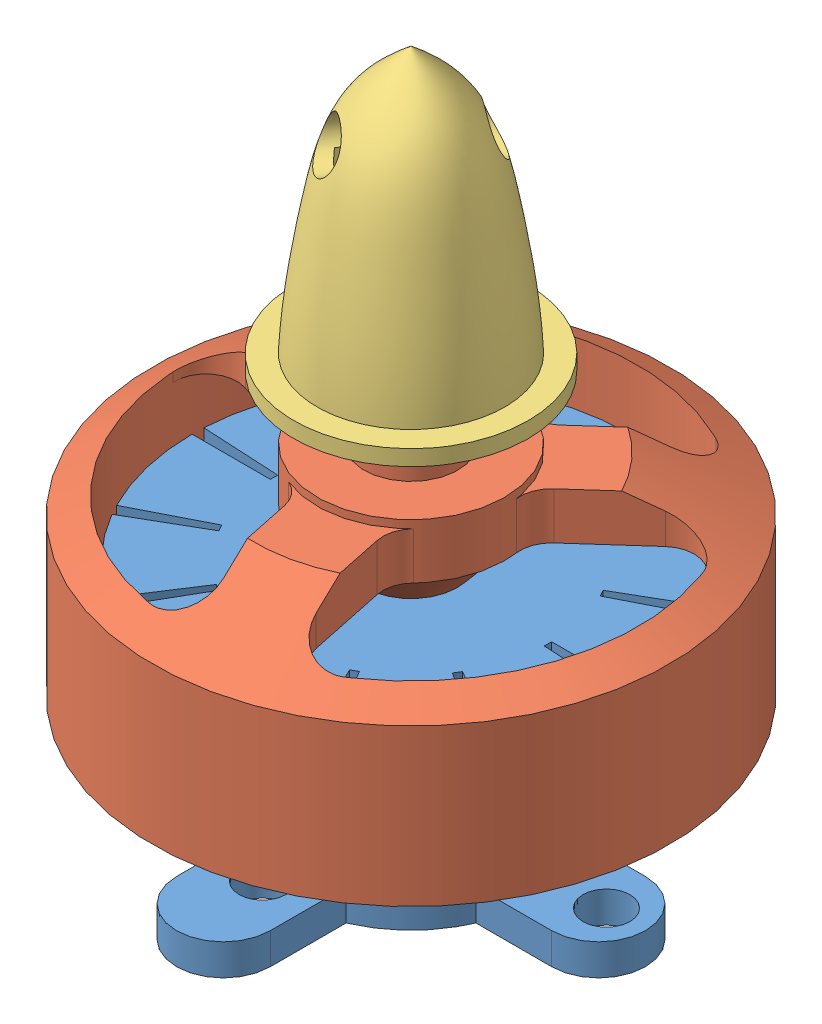
SolidWorks assembly Assem1, configuration Default. Lengths in mm.
Overall size (39.06 43.5 39.06).
3 component instances, 3 part files, 5 mates.
Components (placement in the parent):
- Part2-3: Part2 [Default] at (0 2 0) x (1 0 0) z (0 0 -1) size (30 15 30)
- Part3-1: Part3 [Default] at (0 7.5 0) x (0.204824 0 0.978799) z (-0.978799 0 0.204824) size (33 35.5 33)
- Part4-1: Part4 [Default] at (0 26.5 0) x (-0.572589 0 0.819843) z (-0.819843 0 -0.572589) size (15 18 15)
Mates (geometry in assembly coordinates):
- Coincident13: coincident: plane of Part2-3 through (0 0 0) normal (0 -1 0); point of assembly
- Concentric1: concentric anti-aligned: cylinder of Part2-3 through (0 15 0) axis (0 -1 0) radius 1.5; cylinder of Part3-1 through (0 2 0) axis (0 1 0) radius 1.5
- Coincident15: coincident anti-aligned: plane of Part2-3 through (4 15 0) normal (0 1 0); plane of Part3-1 through (0 15 0) normal (0 -1 0)
- Concentric2: concentric aligned: cylinder of Part3-1 through (0 7.5 0) axis (0 -1 0) radius 3; cylinder of Part4-1 through (0 37.5 0) axis (0 -1 0) radius 3.5
- Distance1: distance = 4 mm anti-aligned: plane of Part4-1 through (0 25.5 0) normal (0 -1 0); plane of Part3-1 through (1.2289 21.5 5.8728) normal (0 1 0)
